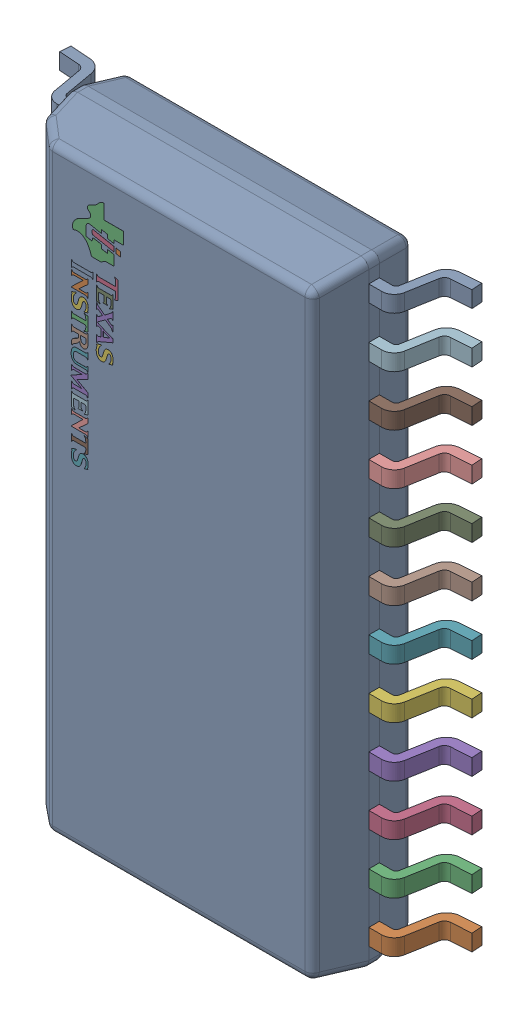
SolidWorks assembly U4, configuration Défaut. Lengths in mm.
Overall size (10.34 15.4 2.65).
28 component instances, 4 part files, 0 mates.
Components (placement in the parent):
- IC_Texas_Instruments_CD74HC4067M96_eec-1: IC_Texas_Instruments_CD74HC4067M96_eec [Défaut] at (-0.127 -28.875 0) x (-1 0 0) z (0 0 1) size (10.34 15.4 2.65)
  - BODY-SO-1: BODY-SO [Défaut] at (0 0 1.0825) x (0 1 0) z (1 0 0) size (15.4 2.45 7.5)
  - LEAD-SO-1: LEAD-SO [Défaut] at (4.315 6.985 0.25) x (0 1 0) z (1 0 0) size (0.41 1.43 1.42)
  - LEAD-SO-2: LEAD-SO [Défaut] at (4.315 5.715 0.25) x (0 1 0) z (1 0 0) size (0.41 1.43 1.42)
  - LEAD-SO-3: LEAD-SO [Défaut] at (4.315 4.445 0.25) x (0 1 0) z (1 0 0) size (0.41 1.43 1.42)
  - LEAD-SO-4: LEAD-SO [Défaut] at (4.315 3.175 0.25) x (0 1 0) z (1 0 0) size (0.41 1.43 1.42)
  - LEAD-SO-5: LEAD-SO [Défaut] at (4.315 1.905 0.25) x (0 1 0) z (1 0 0) size (0.41 1.43 1.42)
  - LEAD-SO-6: LEAD-SO [Défaut] at (4.315 0.635 0.25) x (0 1 0) z (1 0 0) size (0.41 1.43 1.42)
  - LEAD-SO-7: LEAD-SO [Défaut] at (4.315 -0.635 0.25) x (0 1 0) z (1 0 0) size (0.41 1.43 1.42)
  - LEAD-SO-8: LEAD-SO [Défaut] at (4.315 -1.905 0.25) x (0 1 0) z (1 0 0) size (0.41 1.43 1.42)
  - LEAD-SO-9: LEAD-SO [Défaut] at (4.315 -3.175 0.25) x (0 1 0) z (1 0 0) size (0.41 1.43 1.42)
  - LEAD-SO-10: LEAD-SO [Défaut] at (4.315 -4.445 0.25) x (0 1 0) z (1 0 0) size (0.41 1.43 1.42)
  - LEAD-SO-11: LEAD-SO [Défaut] at (4.315 -5.715 0.25) x (0 1 0) z (1 0 0) size (0.41 1.43 1.42)
  - LEAD-SO-12: LEAD-SO [Défaut] at (4.315 -6.985 0.25) x (0 1 0) z (1 0 0) size (0.41 1.43 1.42)
  - LEAD-SO-13: LEAD-SO [Défaut] at (-4.315 6.985 0.25) x (0 -1 0) z (-1 0 0) size (0.41 1.43 1.42)
  - LEAD-SO-14: LEAD-SO [Défaut] at (-4.315 5.715 0.25) x (0 -1 0) z (-1 0 0) size (0.41 1.43 1.42)
  - LEAD-SO-15: LEAD-SO [Défaut] at (-4.315 4.445 0.25) x (0 -1 0) z (-1 0 0) size (0.41 1.43 1.42)
  - LEAD-SO-16: LEAD-SO [Défaut] at (-4.315 3.175 0.25) x (0 -1 0) z (-1 0 0) size (0.41 1.43 1.42)
  - LEAD-SO-17: LEAD-SO [Défaut] at (-4.315 1.905 0.25) x (0 -1 0) z (-1 0 0) size (0.41 1.43 1.42)
  - LEAD-SO-18: LEAD-SO [Défaut] at (-4.315 0.635 0.25) x (0 -1 0) z (-1 0 0) size (0.41 1.43 1.42)
  - LEAD-SO-19: LEAD-SO [Défaut] at (-4.315 -0.635 0.25) x (0 -1 0) z (-1 0 0) size (0.41 1.43 1.42)
  - LEAD-SO-20: LEAD-SO [Défaut] at (-4.315 -1.905 0.25) x (0 -1 0) z (-1 0 0) size (0.41 1.43 1.42)
  - LEAD-SO-21: LEAD-SO [Défaut] at (-4.315 -3.175 0.25) x (0 -1 0) z (-1 0 0) size (0.41 1.43 1.42)
  - LEAD-SO-22: LEAD-SO [Défaut] at (-4.315 -4.445 0.25) x (0 -1 0) z (-1 0 0) size (0.41 1.43 1.42)
  - LEAD-SO-23: LEAD-SO [Défaut] at (-4.315 -5.715 0.25) x (0 -1 0) z (-1 0 0) size (0.41 1.43 1.42)
  - LEAD-SO-24: LEAD-SO [Défaut] at (-4.315 -6.985 0.25) x (0 -1 0) z (-1 0 0) size (0.41 1.43 1.42)
  - Texas Logo Yury-1: Texas Logo Yury [Défaut] at (2.174 -7.1221 2.551) x (0 1 0) z (0 0 1) size (1.32 1.29 0.11)
  - Texas Logo Yury - Copy-1: Texas Logo Yury - Copy [Défaut] at (2.0641 -7.1534 2.551) x (0 1 0) z (0 0 1) size (4.61 1.2 0.1)
